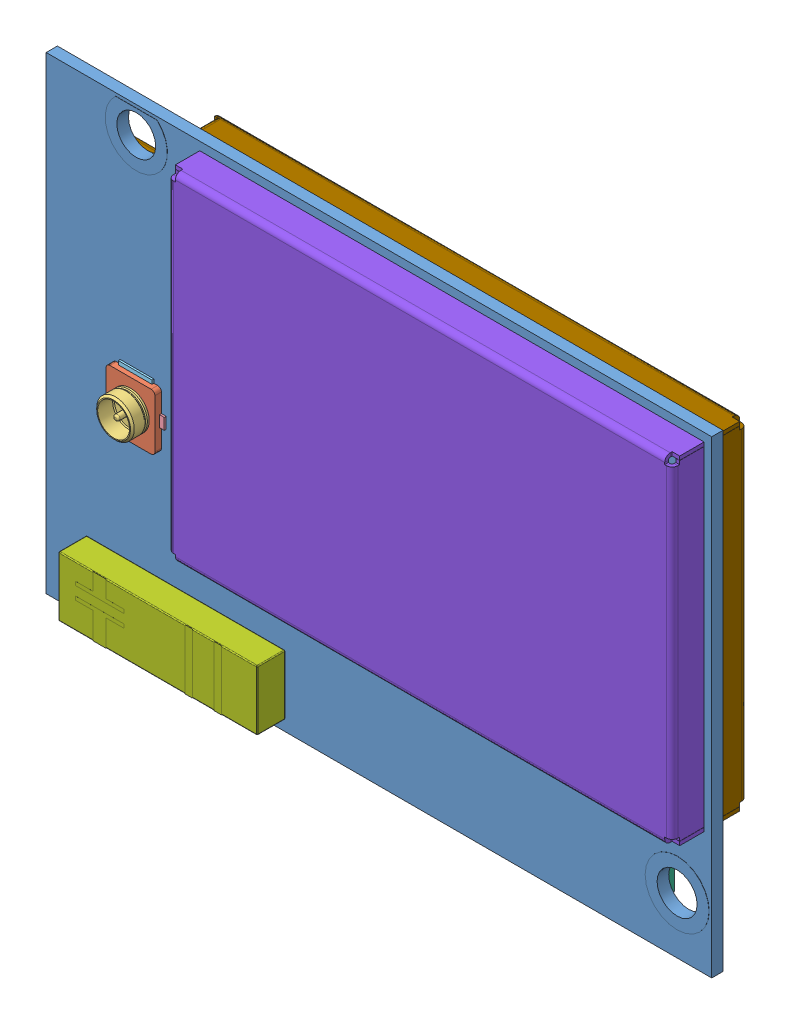
SolidWorks assembly Intel_Edison_(assembly), configuration Default. Lengths in mm.
Overall size (35.5 25 4).
14 component instances, 9 part files, 0 mates.
Components (placement in the parent):
- Intel_Edison_(CI_board)-1: Intel_Edison_(CI_board) [Default] at (-89.0857 12.9564 38.2069) size (35.5 25 0.62)
- Intel_Edison_(assembled_antenna_connector)-1: Intel_Edison_(assembled_antenna_connector) [Default] at (-101.9877 11.5509 38.5069) x (0 1 0) z (0 0 1) size (3.4 3.1 1.25)
  - Intel_Edison_(antenna_connector_1)-1: Intel_Edison_(antenna_connector_1) [Default] at origin size (3 2.6 0.35)
  - Intel_Edison_(antenna_connector_2)-1: Intel_Edison_(antenna_connector_2) [Default] at origin size (2 2 0.9)
  - Intel_Edison_(antenna_connector_3)-1: Intel_Edison_(antenna_connector_3) [Default] at origin size (0.6 0.5 0.1)
  - Intel_Edison_(antenna_connector_4)-1: Intel_Edison_(antenna_connector_4) [Default] at origin size (0.4 1.8 0.1)
  - Intel_Edison_(antenna_connector_4)-2: Intel_Edison_(antenna_connector_4) [Default] at (3 0 0) size (0.4 1.8 0.1)
  - Intel_Edison_(antenna_connector_3)-2: Intel_Edison_(antenna_connector_3) [Default] at (0 -2.6 0) size (0.6 0.5 0.1)
- Intel_Edison_(assembled_hirose_connector)-1: Intel_Edison_(assembled_hirose_connector) [Default] at (9.5952 -18.4665 0.7603) size (17.34 4.2 1.2)
  - Intel_Edison_(Hirose_connector)-1: Intel_Edison_(Hirose_connector) [Default] at (-96.5867 20.4693 35.6966) size (8.86 4.2 1.2)
  - Intel_Edison_(Hirose_connector)-2: Intel_Edison_(Hirose_connector) [Default] at (-89.9273 23.3989 35.6966) x (-1 0 0) z (0 0 1) size (8.86 4.2 1.2)
- Intel_Edison_(antenna)-1: Intel_Edison_(antenna) [Default] at (-89.0595 12.9329 40.0069) size (10.6 3.2 1.5)
- Intel_Edison_(front_box)-1: Intel_Edison_(front_box) [Default] at (-85.1943 16.0126 40.2069) x (1 0 0) z (0 1 0) size (26.9 1.7 18)
- Intel_Edison_(back_box)-1: Intel_Edison_(back_box) [Default] at (-88.5443 16.0126 36.2069) x (-1 0 0) z (0 1 0) size (33.6 1.7 18)
